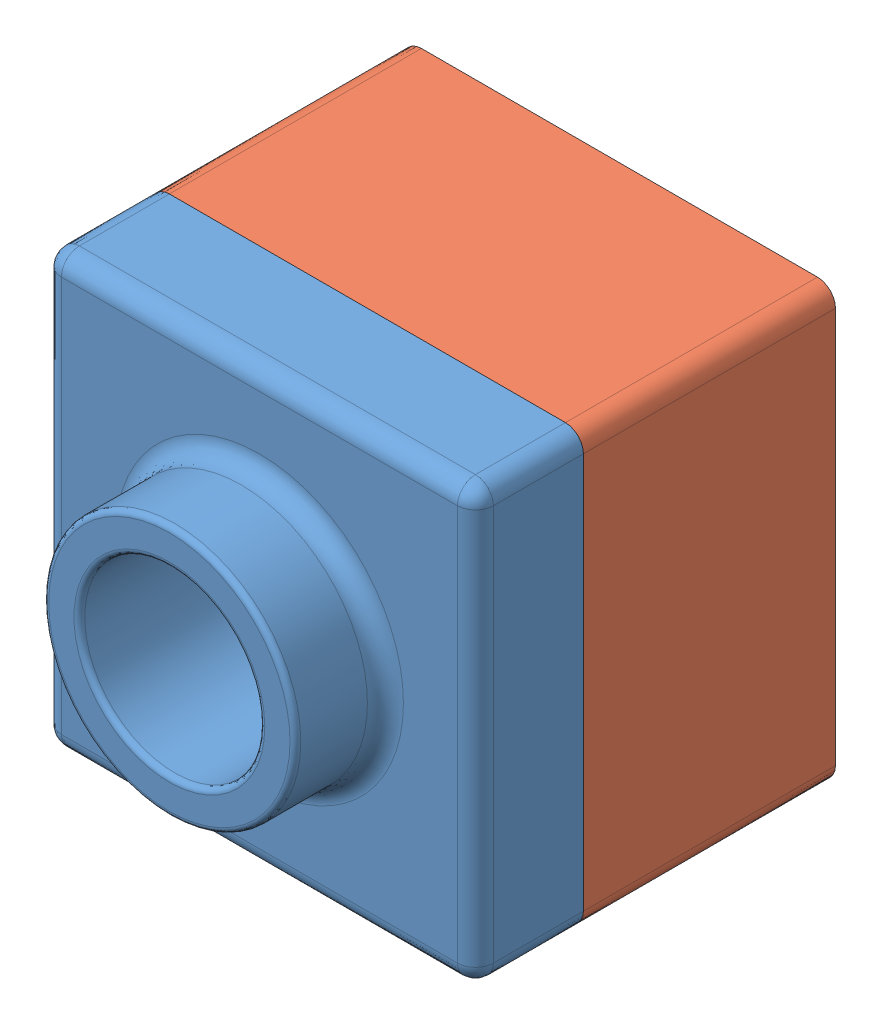
SolidWorks assembly Assem1, configuration Default. Lengths in mm.
Overall size (120 120 125).
2 component instances, 2 part files, 2 mates.
Components (placement in the parent):
- tutorial part-1: tutorial part [Default] at (-8.5731 5.7325 58.9967) size (120 120 55)
- tutorial part 2-1: tutorial part 2 [Default] at (-8.5731 5.7325 -11.0033) size (120 120 90)
Mates (geometry in assembly coordinates):
- Coincident2: coincident: line of tutorial part-1 through (106.4269 125.7325 58.9967) axis (-1 0 0); line of tutorial part 2-1 through (139.73 125.7325 58.9967) axis (-1 0 0)
- Coincident4: coincident aligned: plane of tutorial part-1 through (111.4269 5.7325 88.9967) normal (1 0 0); plane of tutorial part 2-1 through (111.4269 5.7325 78.9967) normal (1 0 0)
